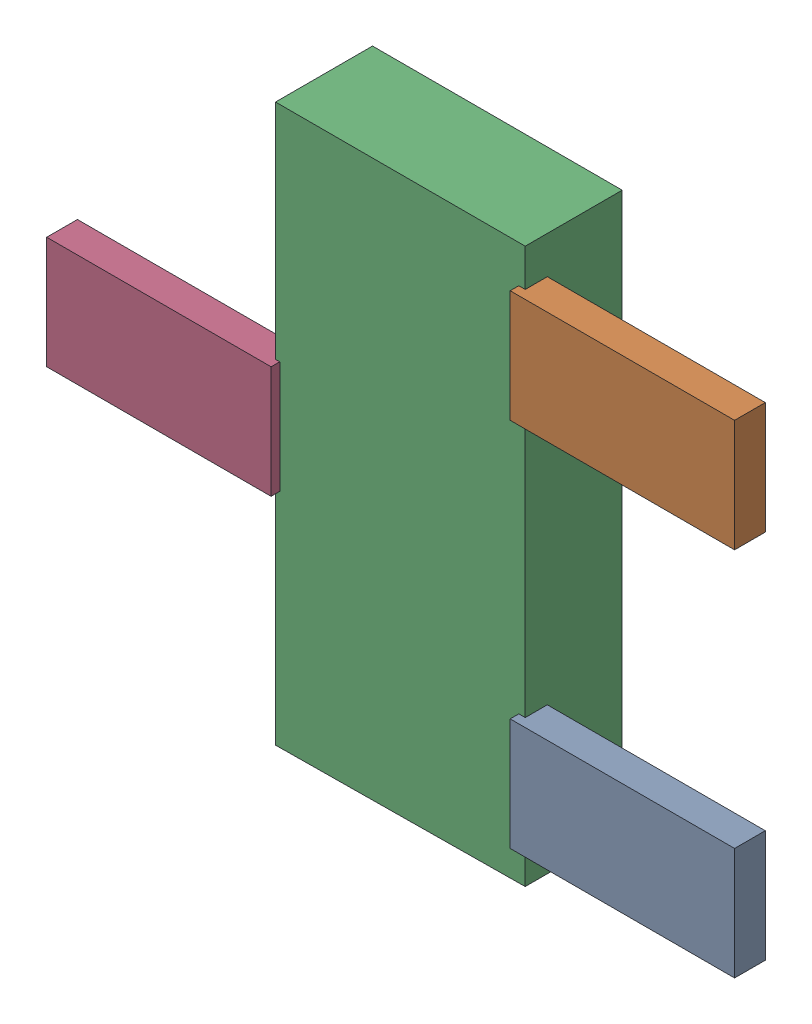
SolidWorks assembly VT2, configuration Default. Lengths in mm.
Overall size (3.58 2.9 0.55).
8 component instances, 2 part files, 0 mates.
Components (placement in the parent):
- 432134544_6-1: 432134544_6 [Default] at (33.9288 50.3927 -0.5715) size (1.17 0.58 0.16)
  - Extruded (38)-1: Extruded (38) [Default] at origin size (1.17 0.58 0.16)
- 432134544_7-1: 432134544_7 [Default] at (33.9288 52.3231 -0.5715) size (1.17 0.58 0.16)
  - Extruded (38)-1: Extruded (38) [Default] at origin size (1.17 0.58 0.16)
- 710423824_2-1: 710423824_2 [Default] at (32.728 51.3604 -0.9615) size (1.3 2.9 0.5)
  - Extruded (39)-1: Extruded (39) [Default] at origin size (1.3 2.9 0.5)
- 432134544_8-1: 432134544_8 [Default] at (31.5158 51.3579 -0.5715) size (1.17 0.58 0.16)
  - Extruded (38)-1: Extruded (38) [Default] at origin size (1.17 0.58 0.16)
